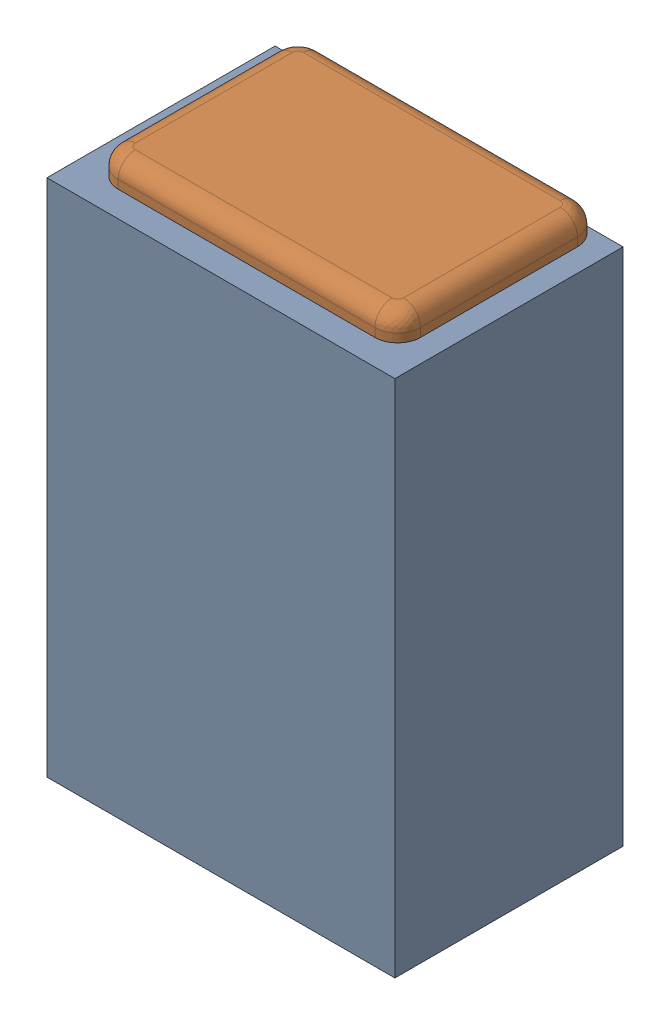
SolidWorks assembly C21, configuration Default. Lengths in mm.
Overall size (0.61 1 0.4).
3 component instances, 2 part files, 0 mates.
Components (placement in the parent):
- 1088881848-1: 1088881848 [Default] at (9.175 5.225 0) size (0.61 0.91 0.4)
  - Extruded-1-1: Extruded-1 [Default] at origin size (0.61 0.91 0.4)
- C0402-1: C0402 [Default] at (9.1749 5.2251 0) x (0 1 0) z (1 0 0) size (1 0.36 0.54)
